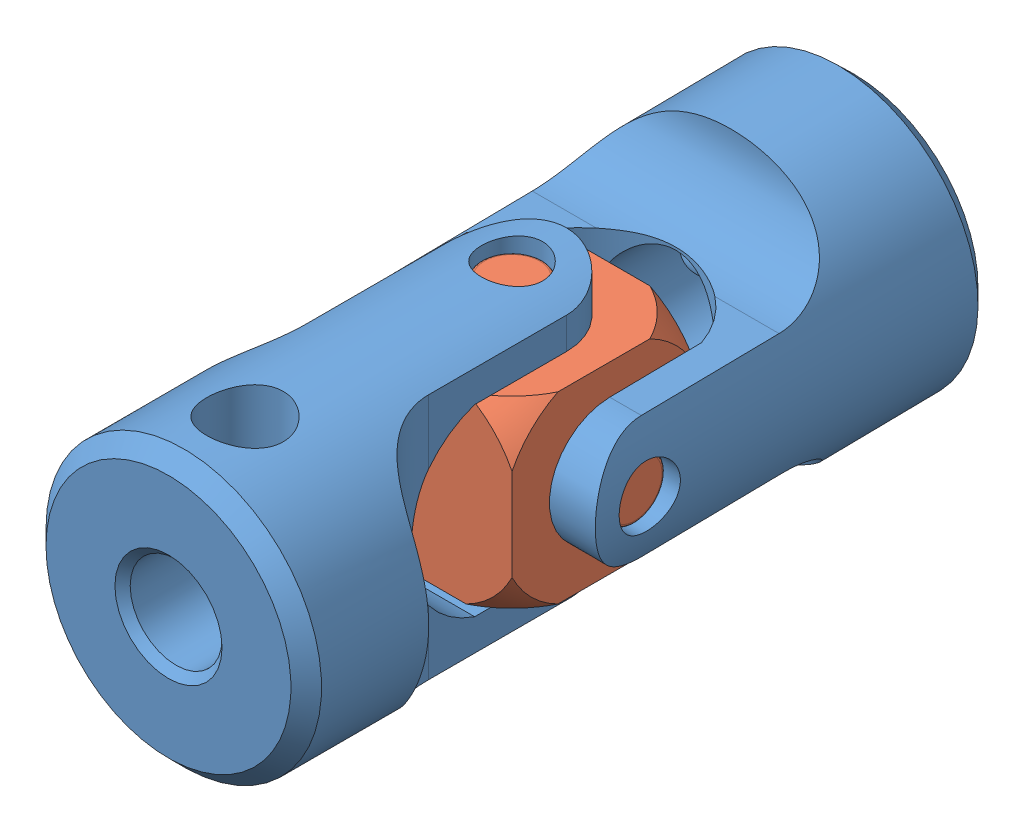
SolidWorks assembly cardan_jiont, configuration 默认. Lengths in mm.
Overall size (9 9.19 22.51).
3 component instances, 2 part files, 4 mates.
Components (placement in the parent):
- cardan-1: cardan [hole3mm] at (7.3749 5.586 -4.6628) size (9 9 13)
- jiont-1: jiont [默认] at (7.3749 5.586 -2.8839) x (1 0 0) z (0 -1 0) size (8 6 8)
- cardan-2: cardan [hole4mm] at (7.3749 5.5598 -1.1052) x (0 -0.999892 -0.014694) z (0 0.014694 -0.999892) size (9 9 13)
Mates (geometry in assembly coordinates):
- 重合1: coincident anti-aligned: plane of cardan-1 through (0.8749 2.586 -4.6628) normal (0 1 0); plane of jiont-1 through (7.3749 2.586 -2.8839) normal (0 -1 0)
- 同心1: concentric aligned: cylinder of cardan-1 through (7.3749 -0.914 -2.8839) axis (0 1 0) radius 1; cylinder of jiont-1 through (7.3749 1.586 -2.8839) axis (0 1 0) radius 1
- 重合2: coincident anti-aligned: plane of jiont-1 through (10.3749 2.586 0.1161) normal (1 0 0); plane of cardan-2 through (10.3749 12.0591 -1.0097) normal (-1 0 0)
- 同心2: concentric aligned: cylinder of jiont-1 through (11.3749 5.586 -2.8839) axis (-1 0 0) radius 1; cylinder of cardan-2 through (13.8749 5.586 -2.8839) axis (-1 0 0) radius 1
